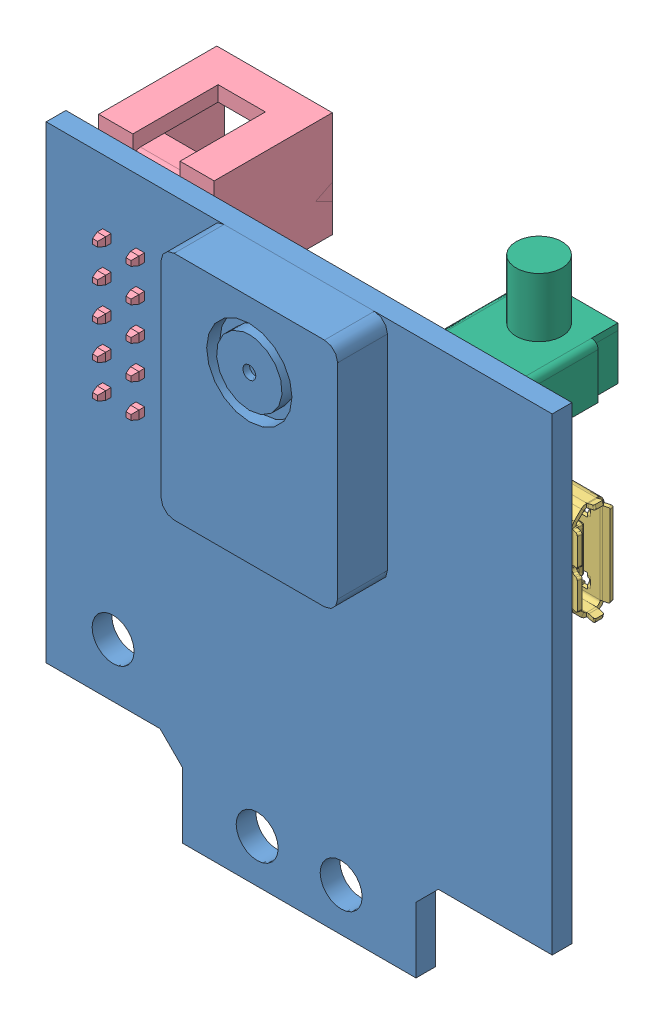
SolidWorks assembly Pixy 2, configuration Default. Lengths in mm.
Overall size (39.17 46.9 15.65).
7 component instances, 6 part files, 22 mates.
Components (placement in the parent):
- pixy-1: pixy [Default] x (1 0 0) z (0 -1 0) size (38.55 5.3 42.4)
- capacitor-1: capacitor [По умолчанию] at (-1.8911 -10.6395 0) x (-1 0 0) z (0 0 -1) size (7.71 6.82 6.76)
- micro usb-1: micro usb [По умолчанию] at (16.275 6.9 0) x (1 0 0) z (0 0 -1) size (5.84 7.77 3.4)
- DS1013-10SSiB-1: DS1013-10SSiB [Default] at (-12.105 12.63 -0.7) x (0 -1 0) z (0 0 -1) size (20.6 9.1 12.4)
- DS1022-1x3RD61-1: DS1022-1x3RD61 [По умолчанию] at (-10.575 -4.5 -0.32) x (0 -1 0) z (-1 0 0) size (7.62 10.35 5.5)
- DS1022-1x3RD61-2: DS1022-1x3RD61 [По умолчанию] at (-15.575 -9.58 -0.32) x (0 1 0) z (1 0 0) size (7.62 10.35 5.5)
- button-1: button [Default] at (15.775 17.35 0) x (1 0 0) z (0 1 0) size (7 7 11.5)
Mates (geometry in assembly coordinates):
- Совпадение1: coincident: plane of pixy-1 through (0 0 0) normal (0 0 -1); plane of micro usb-1 through (16.775 15.4582 0) normal (0 0 1)
- Совпадение2: coincident: plane of pixy-1 through (0 0 0) normal (0 0 -1); plane of capacitor-1 through (-1.8827 -10.6395 0) normal (0 0 1)
- Расстояние1: distance = 10.5 mm: plane of pixy-1 through (-8.9 -24.55 1.5) normal (0 -1 0); plane of capacitor-1 through (1.2173 -14.05 0) normal (0 -1 0)
- Расстояние2: distance = 14 mm: plane of capacitor-1 through (-5.275 -12.7646 0) normal (-1 0 0); plane of pixy-1 through (-19.275 17.85 1.5) normal (-1 0 0)
- Расстояние3: distance = 7.2 mm: plane of micro usb-1 through (16.775 10.65 -5.6597) normal (0 1 0); plane of pixy-1 through (-19.275 17.85 1.5) normal (0 1 0)
- Совпадение6: coincident: line of pixy-1 through (35.7 19.275 17.85) axis (0 0 -1); line of micro usb-1 through (19.275 6.9029 0) axis (0 1 0)
- Расстояние4: distance = 1 mm: plane of pixy-1 through (0 0 0) normal (0 0 -1); plane of DS1013-10SSiB-1 through (-12.105 12.63 -1) normal (0 0 1)
- Совпадение8: coincident: plane of pixy-1 through (-19.275 17.85 1.5) normal (0 1 0); plane of DS1013-10SSiB-1 through (-17.775 17.85 -1) normal (0 1 0)
- Расстояние5: distance = 1.5 mm: plane of DS1013-10SSiB-1 through (-17.775 -2.75 -1) normal (-1 0 0); plane of pixy-1 through (-19.275 17.85 1.5) normal (-1 0 0)
- Совпадение10: coincident: plane of pixy-1 through (0 0 0) normal (0 0 -1); plane of DS1022-1x3RD61-1 through (-10.575 -4.18 0) normal (0 0 1)
- Параллельность1: parallel: plane of pixy-1 through (-19.275 17.85 1.5) normal (-1 0 0); plane of DS1022-1x3RD61-1 through (-10.575 -5.1853 -4.35) normal (1 0 0)
- Совпадение11: coincident: plane of DS1022-1x3RD61-1 through (-13.075 -3.8147 -4.35) normal (-1 0 0); plane of DS1022-1x3RD61-2 through (-13.075 -5.1853 -4.35) normal (1 0 0)
- Совпадение12: coincident: plane of DS1022-1x3RD61-1 through (-10.575 -4.5 -4.35) normal (0 0 -1); plane of DS1022-1x3RD61-2 through (-15.575 -4.5 -4.35) normal (0 0 -1)
- Совпадение13: coincident: plane of DS1022-1x3RD61-1 through (-11.075 -3.23 -4.35) normal (0 1 0); plane of DS1022-1x3RD61-2 through (-13.575 -3.23 -4.35) normal (0 1 0)
- Расстояние6: distance = 3.7 mm: plane of DS1022-1x3RD61-2 through (-15.575 -3.8147 -4.35) normal (-1 0 0); plane of pixy-1 through (-19.275 17.85 1.5) normal (-1 0 0)
- Расстояние7: distance = 7 mm: plane of DS1022-1x3RD61-2 through (-15.075 -10.85 -4.35) normal (0 -1 0); plane of pixy-1 through (-19.275 -17.85 1.5) normal (0 -1 0)
- Совпадение16: coincident: plane of pixy-1 through (-19.275 17.85 1.5) normal (0 1 0); plane of button-1 through (15.775 17.85 0) normal (0 1 0)
- Совпадение17: coincident: plane of pixy-1 through (0 0 0) normal (0 0 -1); plane of button-1 through (16.275 17.35 0) normal (0 0 1)
- Расстояние8: distance = 3 mm: plane of button-1 through (16.275 17.35 0) normal (1 0 0); plane of pixy-1 through (19.275 17.85 1.5) normal (1 0 0)
- Параллельность3: parallel: plane of pixy-1 through (0 0 1.5) normal (0 0 1); plane of assembly through (0 0 0) normal (0 0 1)
- Совпадение19: coincident: point of pixy-1; point of assembly
- Параллельность4: parallel: plane of pixy-1 through (19.275 17.85 1.5) normal (1 0 0); plane of assembly through (0 0 0) normal (1 0 0)
